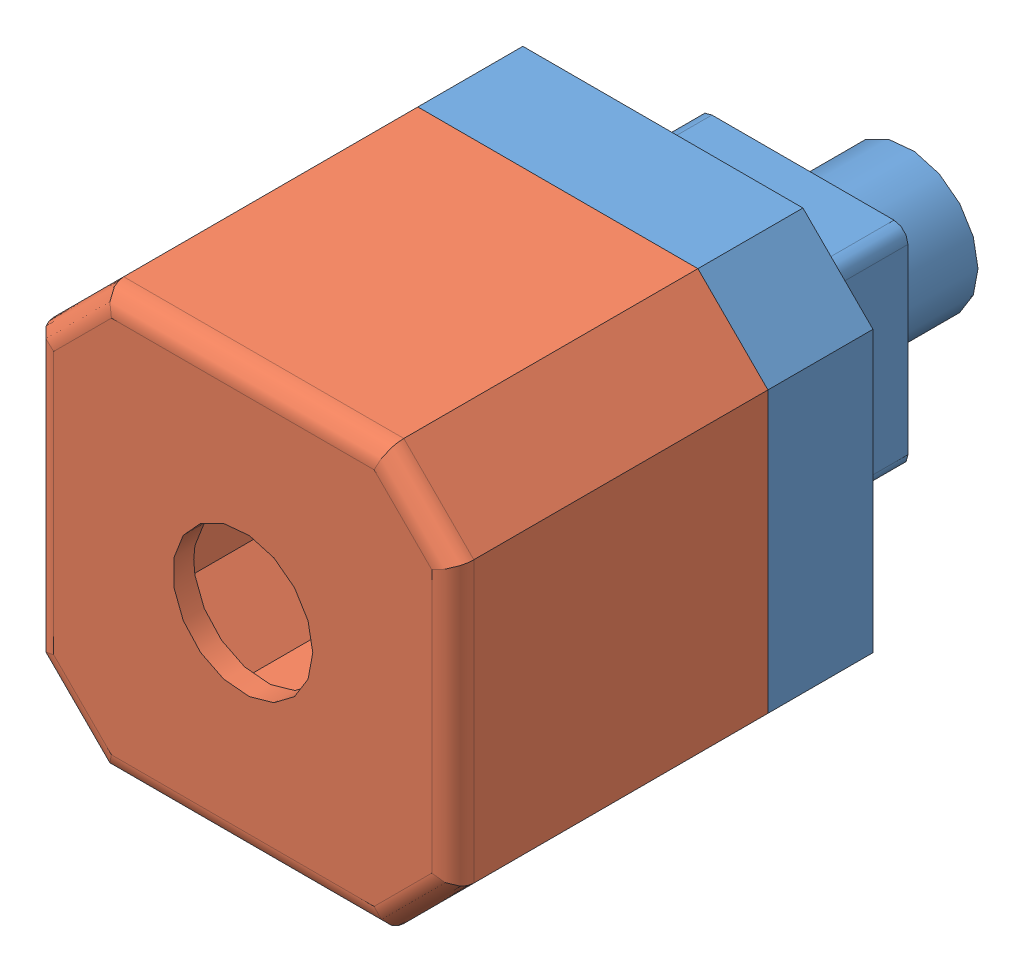
SolidWorks assembly Housing assembly 1, configuration Default. Lengths in mm.
Overall size (60 60 95).
2 component instances, 2 part files, 3 mates.
Components (placement in the parent):
- Housing Cover 2-1: Housing Cover 2 [Default] at (-42.3541 61.8859 27.2082) x (-1 0 0) z (0 0 -1) size (60 60 50)
- Housing_base_2-1: Housing_base_2 [Default] at (-72.3541 31.8859 22.2082) size (60 60 50)
Mates (geometry in assembly coordinates):
- Coincident1: coincident: line of Housing Cover 2-1 through (-62.3541 91.8859 27.2082) axis (1 0 0); line of Housing_base_2-1 through (-62.3541 91.8859 27.2082) axis (1 0 0)
- Coincident2: coincident: plane of Housing Cover 2-1 through (-72.3541 105.7833 21.5636) normal (-1 0 0); plane of Housing_base_2-1 through (-72.3541 31.8859 72.2082) normal (-1 0 0)
- Coincident3: coincident aligned: plane of Housing Cover 2-1 through (-12.3541 91.8859 12.2082) normal (0 1 0); plane of Housing_base_2-1 through (-72.3541 91.8859 72.2082) normal (0 1 0)
